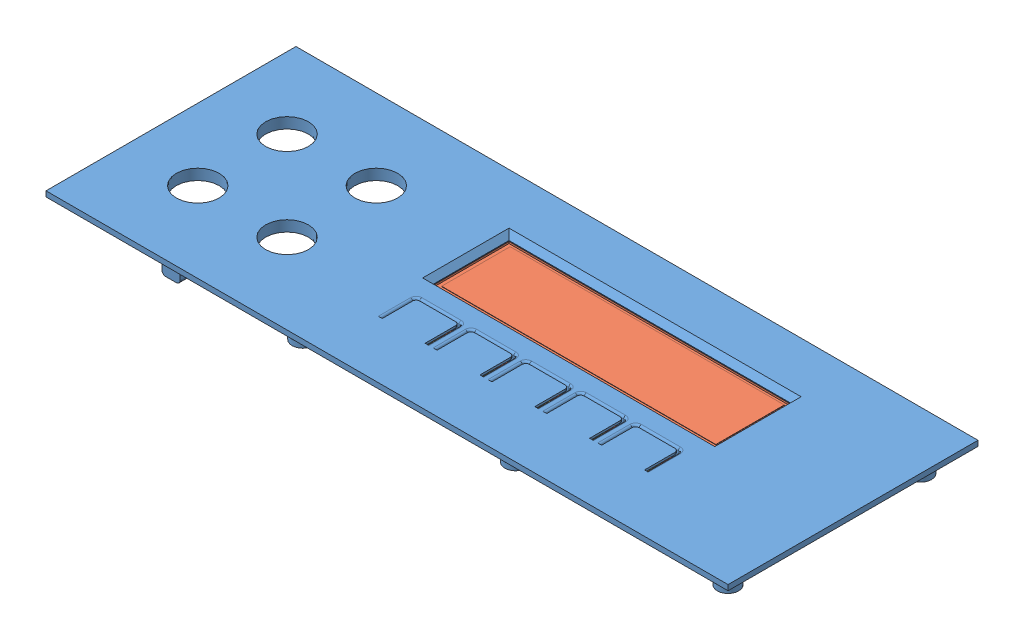
SolidWorks assembly front_panel_assy, configuration Default. Lengths in mm.
Overall size (191 8.05 70).
8 component instances, 4 part files, 22 mates.
Components (placement in the parent):
- front_3mm-1: front_3mm [Default] at (-75.2377 22.9171 25.8875) size (191 8.05 70)
- display-2: display [Default] at (-2.2954 20.3671 9.8025) size (100.5 6.3 33.5)
- PCB_sworks-1: PCB_sworks [Default] at (-95.1947 16.2671 23.6389) x (1 0 0) z (0 1 0) size (125 60 1.6) (hidden)
- alps_SKPMAME010-1: alps_SKPMAME010 [Default] at (-61.3937 17.8671 33.2189) size (6.7 5 6)
- alps_SKPMAME010-16: alps_SKPMAME010 [Default] at (-76.7537 17.8671 33.2189) size (6.7 5 6)
- alps_SKPMAME010-17: alps_SKPMAME010 [Default] at (-92.1137 17.8671 33.2189) size (6.7 5 6)
- alps_SKPMAME010-18: alps_SKPMAME010 [Default] at (-107.4737 17.8671 33.2189) size (6.7 5 6)
- alps_SKPMAME010-19: alps_SKPMAME010 [Default] at (-122.8337 17.8671 33.2189) size (6.7 5 6)
Mates (geometry in assembly coordinates):
- Coincident2: coincident anti-aligned: plane of front_3mm-1 through (-149.1754 25.9171 12.6505) normal (0 0 -1); plane of PCB-1 through (-123.7946 60.1075 12.6505) normal (0 0 1)
- Coincident3: coincident anti-aligned: plane of front_3mm-1 through (-99.1754 25.9171 -5.3495) normal (-1 0 0); plane of PCB-1 through (-99.1754 60.1075 -4.8496) normal (1 0 0)
- Coincident4: coincident aligned: plane of front_3mm-1 through (-75.2377 25.9171 25.8875) normal (0 1 0); plane of PCB-1 through (-145.8385 25.9171 48.8584) normal (0 1 0)
- Distance2: distance = 1.25 mm anti-aligned: plane of front_3mm-1 through (-75.2377 22.9171 25.8875) normal (0 -1 0); plane of display-2 through (-2.2954 24.1671 9.8025) normal (0 1 0)
- Coincident12: coincident anti-aligned: plane of display-2 through (-2.2954 17.8671 9.8025) normal (0 -1 0); plane of PCB_sworks-1 through (-95.1947 17.8671 23.6389) normal (0 1 0)
- Distance5: distance = 2.5 mm aligned: plane of front_3mm-1 through (-205.1976 229.3403 -12.8495) normal (0 0 -1); plane of PCB_sworks-1 through (-146.6976 17.8671 -10.3495) normal (0 0 -1)
- Distance6: distance = 2.5 mm aligned: plane of front_3mm-1 through (-19.1976 229.3403 -12.8495) normal (1 0 0); plane of PCB_sworks-1 through (-21.6976 17.8671 -10.3495) normal (1 0 0)
- Concentric1: concentric anti-aligned: circle of alps_SKPMAME010-1; circle of front_3mm-1
- Parallel1: parallel aligned: plane of front_3mm-1 through (-19.1976 229.3403 52.1505) normal (0 0 1); plane of alps_SKPMAME010-1 through (-64.2483 21.3671 36.5466) normal (0 0 1)
- Coincident16: coincident anti-aligned: plane of PCB_sworks-1 through (-95.1947 17.8671 23.6389) normal (0 1 0); plane of alps_SKPMAME010-1 through (-61.3937 17.8671 33.2189) normal (0 -1 0)
- Parallel14: parallel aligned: plane of front_3mm-1 through (-19.1976 229.3403 52.1505) normal (0 0 1); plane of alps_SKPMAME010-16 through (-79.6083 21.3671 36.5466) normal (0 0 1)
- Coincident17: coincident anti-aligned: plane of PCB_sworks-1 through (-95.1947 17.8671 23.6389) normal (0 1 0); plane of alps_SKPMAME010-16 through (-76.7537 17.8671 33.2189) normal (0 -1 0)
- Concentric12: concentric anti-aligned: circle of front_3mm-1; circle of alps_SKPMAME010-16
- Parallel15: parallel aligned: plane of front_3mm-1 through (-19.1976 229.3403 52.1505) normal (0 0 1); plane of alps_SKPMAME010-17 through (-94.9683 21.3671 36.5466) normal (0 0 1)
- Coincident18: coincident anti-aligned: plane of PCB_sworks-1 through (-95.1947 17.8671 23.6389) normal (0 1 0); plane of alps_SKPMAME010-17 through (-92.1137 17.8671 33.2189) normal (0 -1 0)
- Concentric13: concentric anti-aligned: circle of front_3mm-1; circle of alps_SKPMAME010-17
- Parallel16: parallel aligned: plane of front_3mm-1 through (-19.1976 229.3403 52.1505) normal (0 0 1); plane of alps_SKPMAME010-18 through (-110.3283 21.3671 36.5466) normal (0 0 1)
- Coincident19: coincident anti-aligned: plane of PCB_sworks-1 through (-95.1947 17.8671 23.6389) normal (0 1 0); plane of alps_SKPMAME010-18 through (-107.4737 17.8671 33.2189) normal (0 -1 0)
- Concentric14: concentric anti-aligned: circle of front_3mm-1; circle of alps_SKPMAME010-18
- Parallel17: parallel aligned: plane of front_3mm-1 through (-19.1976 229.3403 52.1505) normal (0 0 1); plane of alps_SKPMAME010-19 through (-125.6883 21.3671 36.5466) normal (0 0 1)
- Coincident20: coincident anti-aligned: plane of PCB_sworks-1 through (-95.1947 17.8671 23.6389) normal (0 1 0); plane of alps_SKPMAME010-19 through (-122.8337 17.8671 33.2189) normal (0 -1 0)
- Concentric15: concentric anti-aligned: circle of front_3mm-1; circle of alps_SKPMAME010-19
